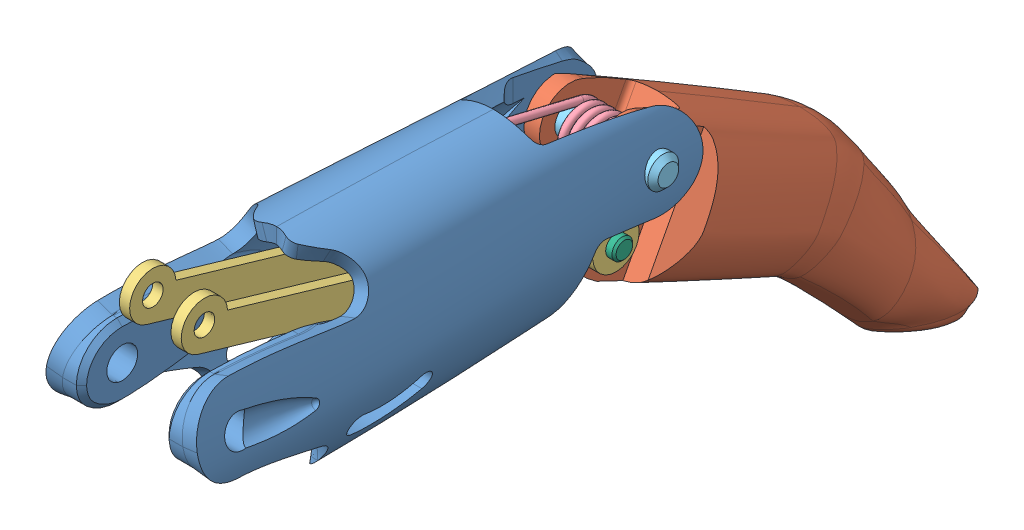
SolidWorks assembly 02-002, configuration 默认. Lengths in mm.
Overall size (17.28 41.98 87.43).
7 component instances, 6 part files, 12 mates.
Components (placement in the parent):
- 01-014-1: 01-014 [默认] at (0.7399 24.4666 56.0052) size (17.28 19.24 50.6)
- 01-015-1: 01-015 [默认] at (0.7399 24.5902 15.6905) x (1 0 0) z (0 0.468665 0.883376) size (12.29 17.46 47.7)
- 01-016-1: 01-016 [默认] at (-2.2601 19.3354 11.1202) x (-1 0 0) z (0 -0.281069 -0.959688) size (1 6 46.5)
- 01-016-2: 01-016 [默认] at (2.7399 19.3354 11.1202) x (-1 0 0) z (0 -0.281069 -0.959688) size (1 6 46.5)
- 01-009-1: 01-009 [默认] at (-1.1486 26.3601 10.0439) x (1 0 0) z (0 -0.983519 0.180804) size (5.44 18.26 4.7)
- 01-035-1: 01-035 [默认] at (-6.2601 26.6907 10.048) x (0 -0.54919 0.835698) z (-1 0 0) size (3 3 14)
- 01-036-1: 01-036 [默认] at (5.7489 19.3354 11.1202) x (0 -0.452542 -0.891743) z (1 0 0) size (2 2 7.6)
Mates (geometry in assembly coordinates):
- Concentric1: concentric anti-aligned: cylinder of 01-015-1 through (0.7349 26.6907 10.048) axis (1 0 0) radius 1.5; cylinder of 01-035-1 through (-6.2601 26.6907 10.048) axis (-1 0 0) radius 1.5
- Concentric2: concentric anti-aligned: cylinder of 01-014-1 through (9.378 26.6907 10.048) axis (-1 0 0) radius 1.5; cylinder of 01-015-1 through (0.7349 26.6907 10.048) axis (1 0 0) radius 1.5
- Width2: width anti-aligned: plane of 01-035-1 through (-6.2601 26.6907 10.048) normal (-1 0 0); plane of 01-035-1 through (7.7399 26.6907 10.048) normal (1 0 0); plane of 01-015-1 through (4.7399 16.2209 20.1307) normal (1 0 0); plane of 01-015-1 through (-3.2601 16.2209 20.1307) normal (-1 0 0)
- Width3: width aligned: plane of 01-014-1 through (4.7399 24.4185 13.6229) normal (-1 0 0); plane of 01-014-1 through (-3.2601 24.4185 13.6229) normal (1 0 0); plane of 01-015-1 through (-3.2601 16.2209 20.1307) normal (-1 0 0); plane of 01-015-1 through (4.7399 16.2209 20.1307) normal (1 0 0)
- Concentric5: concentric aligned: cylinder of 01-016-2 through (3.7399 19.3354 11.1202) axis (-1 0 0) radius 1; cylinder of 01-036-1 through (-4.2511 19.3354 11.1202) axis (-1 0 0) radius 1
- Coincident2: coincident anti-aligned: plane of 01-015-1 through (2.7399 23.8332 12.13) normal (1 0 0); plane of 01-016-2 through (2.7399 19.3354 11.1202) normal (-1 0 0)
- Coincident3: coincident anti-aligned: plane of 01-015-1 through (-1.2601 23.8332 12.13) normal (-1 0 0); plane of 01-016-1 through (-1.2601 19.3354 11.1202) normal (1 0 0)
- Concentric6: concentric aligned: cylinder of 01-016-1 through (-1.2601 32.5798 51.0055) axis (-1 0 0) radius 1; cylinder of 01-016-2 through (3.7399 32.5798 51.0055) axis (-1 0 0) radius 1
- Lock1: lock: unknown of 01-009-1; unknown of 01-035-1
- Lock2: lock: unknown of 01-014-1; unknown of 01-009-1
- Concentric7: concentric anti-aligned: cylinder of 01-015-1 through (-1.2601 19.3354 11.1202) axis (1 0 0) radius 1; cylinder of 01-036-1 through (-4.2511 19.3354 11.1202) axis (-1 0 0) radius 1
- Concentric8: concentric aligned: cylinder of 01-016-1 through (-1.2601 19.3354 11.1202) axis (-1 0 0) radius 2.25; cylinder of 01-036-1 through (-4.2511 19.3354 11.1202) axis (-1 0 0) radius 1
